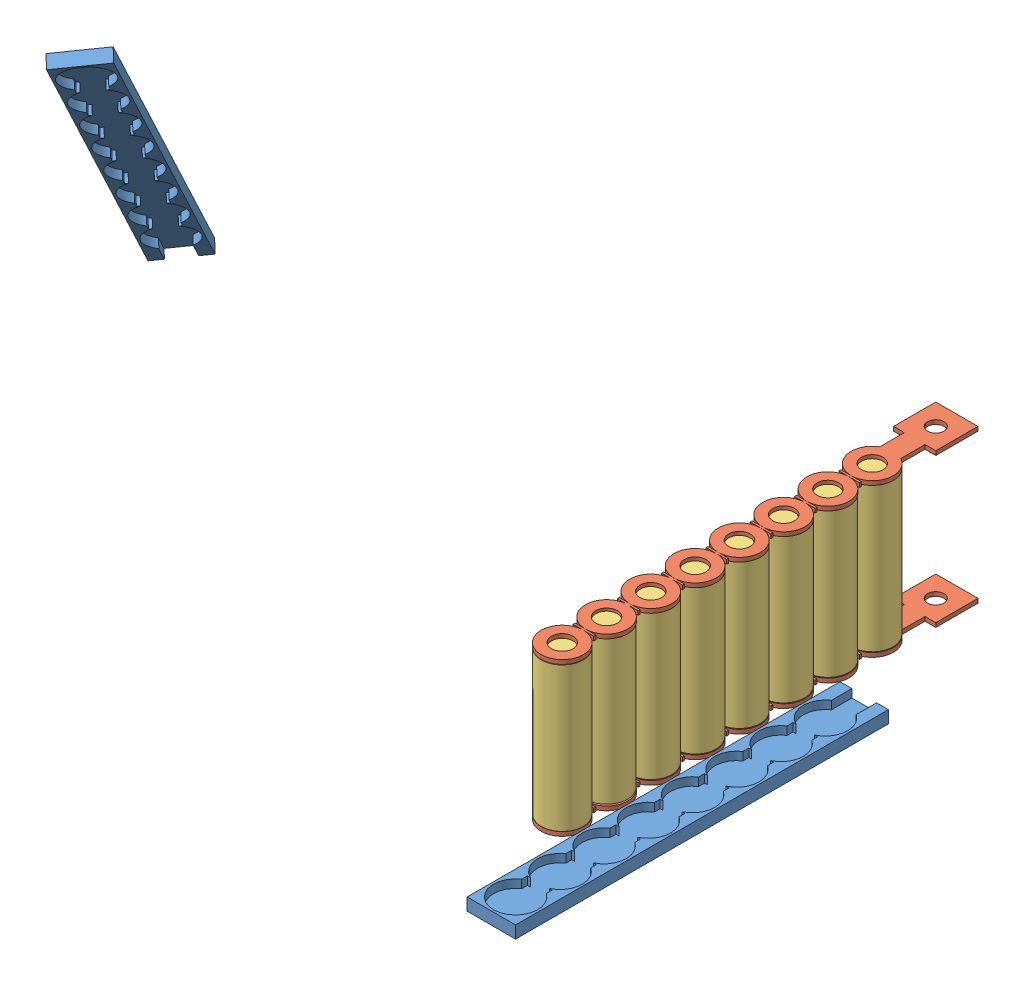
SolidWorks assembly BatteryAssemblyJustBusbar, configuration Default. Lengths in mm.
Overall size (217.86 333.72 328.17).
12 component instances, 3 part files, 18 mates.
Components (placement in the parent):
- BatteryCover_Draft4-1: BatteryCover_Draft4 [Default] at origin size (23.5 6 181)
- BatteryBusbar_Draft-1: BatteryBusbar_Draft [Default] at (-43.2264 -21.186 -250.2235) size (20.67 2.01 202)
- 20700ACell-1: 20700ACell [Default] at (-32.8089 -21.186 -78.9805) size (20.35 70.3 20.35)
- 20700ACell-2: 20700ACell [Default] at (-32.8089 -20.4828 -100.4795) size (20.35 70.3 20.35)
- 20700ACell-3: 20700ACell [Default] at (-32.8089 -20.886 -207.9745) size (20.35 70.3 20.35)
- 20700ACell-4: 20700ACell [Default] at (-32.8089 -20.886 -229.4735) size (20.35 70.3 20.35)
- 20700ACell-5: 20700ACell [Default] at (-32.8089 -20.886 -121.9785) size (20.35 70.3 20.35)
- 20700ACell-6: 20700ACell [Default] at (-32.8089 -20.886 -143.4775) size (20.35 70.3 20.35)
- 20700ACell-7: 20700ACell [Default] at (-32.8089 -20.886 -186.4755) size (20.35 70.3 20.35)
- 20700ACell-8: 20700ACell [Default] at (-32.8089 -20.886 -164.9765) size (20.35 70.3 20.35)
- BatteryBusbar_Draft-2: BatteryBusbar_Draft [Default] at (-43.2264 51.114 -250.2235) size (20.67 2.01 202)
- BatteryCover_Draft4-2: BatteryCover_Draft4 [Default] at (-129.148 307.2787 42.4821) x (-0.750217 -0.1774 0.636948) z (0.242487 0.822392 0.514657) size (23.5 6 181)
Mates (geometry in assembly coordinates):
- Coincident1: coincident anti-aligned: plane of BatteryCover_Draft4-1 through (11.75 -4 -11.75) normal (0 1 0); plane of BatteryBusbar_Draft-1 through (11.75 -4 -162.243) normal (0 -1 0)
- Concentric2: concentric aligned: cylinder of BatteryCover_Draft4-1 through (11.75 -4 -11.75) axis (0 1 0) radius 10.75; cylinder of BatteryBusbar_Draft-1 through (11.75 -4 -11.75) axis (0 1 0) radius 10.25
- Parallel2: parallel anti-aligned: plane of 20700ACell-1 through (-32.8089 49.114 -78.9805) normal (0 1 0); plane of BatteryBusbar_Draft-2 through (-32.8089 49.114 -78.9805) normal (0 -1 0)
- Concentric3: concentric anti-aligned: cylinder of 20700ACell-2 through (-32.8089 49.8172 -100.4795) axis (0 -1 0) radius 5.25; cylinder of BatteryBusbar_Draft-2 through (-32.8089 49.114 -100.4795) axis (0 1 0) radius 5.25
- Coincident10: coincident anti-aligned: plane of 20700ACell-5 through (-32.8089 49.114 -121.9785) normal (0 1 0); plane of BatteryBusbar_Draft-2 through (-32.8089 49.114 -121.9785) normal (0 -1 0)
- Concentric8: concentric anti-aligned: cylinder of 20700ACell-5 through (-32.8089 49.414 -121.9785) axis (0 -1 0) radius 5.25; cylinder of BatteryBusbar_Draft-2 through (-32.8089 49.114 -121.9785) axis (0 1 0) radius 5.25
- Coincident12: coincident anti-aligned: plane of 20700ACell-6 through (-32.8089 49.114 -143.4775) normal (0 1 0); plane of BatteryBusbar_Draft-2 through (-32.8089 49.114 -143.4775) normal (0 -1 0)
- Concentric9: concentric anti-aligned: cylinder of 20700ACell-6 through (-32.8089 49.414 -143.4775) axis (0 -1 0) radius 5.25; cylinder of BatteryBusbar_Draft-2 through (-32.8089 49.114 -143.4775) axis (0 1 0) radius 5.25
- Coincident13: coincident anti-aligned: plane of 20700ACell-8 through (-32.8089 49.114 -164.9765) normal (0 1 0); plane of BatteryBusbar_Draft-2 through (-32.8089 49.114 -164.9765) normal (0 -1 0)
- Concentric10: concentric anti-aligned: cylinder of 20700ACell-8 through (-32.8089 49.414 -164.9765) axis (0 -1 0) radius 5.25; cylinder of BatteryBusbar_Draft-2 through (-32.8089 49.114 -164.9765) axis (0 1 0) radius 5.25
- Coincident15: coincident aligned: plane of 20700ACell-7 through (-32.8089 49.114 -186.4755) normal (0 1 0); circle of BatteryBusbar_Draft-2
- Concentric11: concentric anti-aligned: cylinder of 20700ACell-7 through (-32.8089 49.414 -186.4755) axis (0 -1 0) radius 5.25; cylinder of BatteryBusbar_Draft-2 through (-32.8089 49.114 -186.4755) axis (0 1 0) radius 5.25
- Coincident16: coincident anti-aligned: plane of 20700ACell-3 through (-32.8089 49.114 -207.9745) normal (0 1 0); plane of BatteryBusbar_Draft-2 through (-32.8089 49.114 -207.9745) normal (0 -1 0)
- Concentric12: concentric anti-aligned: cylinder of 20700ACell-3 through (-32.8089 49.414 -207.9745) axis (0 -1 0) radius 5.25; cylinder of BatteryBusbar_Draft-2 through (-32.8089 49.114 -207.9745) axis (0 1 0) radius 5.25
- Coincident18: coincident aligned: plane of 20700ACell-4 through (-32.8089 49.114 -229.4735) normal (0 1 0); circle of BatteryBusbar_Draft-2
- Concentric13: concentric anti-aligned: cylinder of 20700ACell-4 through (-32.8089 49.414 -229.4735) axis (0 -1 0) radius 5.25; cylinder of BatteryBusbar_Draft-2 through (-32.8089 49.114 -229.4735) axis (0 1 0) radius 5.25
- Coincident21: coincident: circle of BatteryBusbar_Draft-1; plane of 20700ACell-1 through (-32.8089 -21.186 -78.9805) normal (0 -1 0)
- Concentric14: concentric aligned: circle of BatteryBusbar_Draft-1; circle of 20700ACell-1
